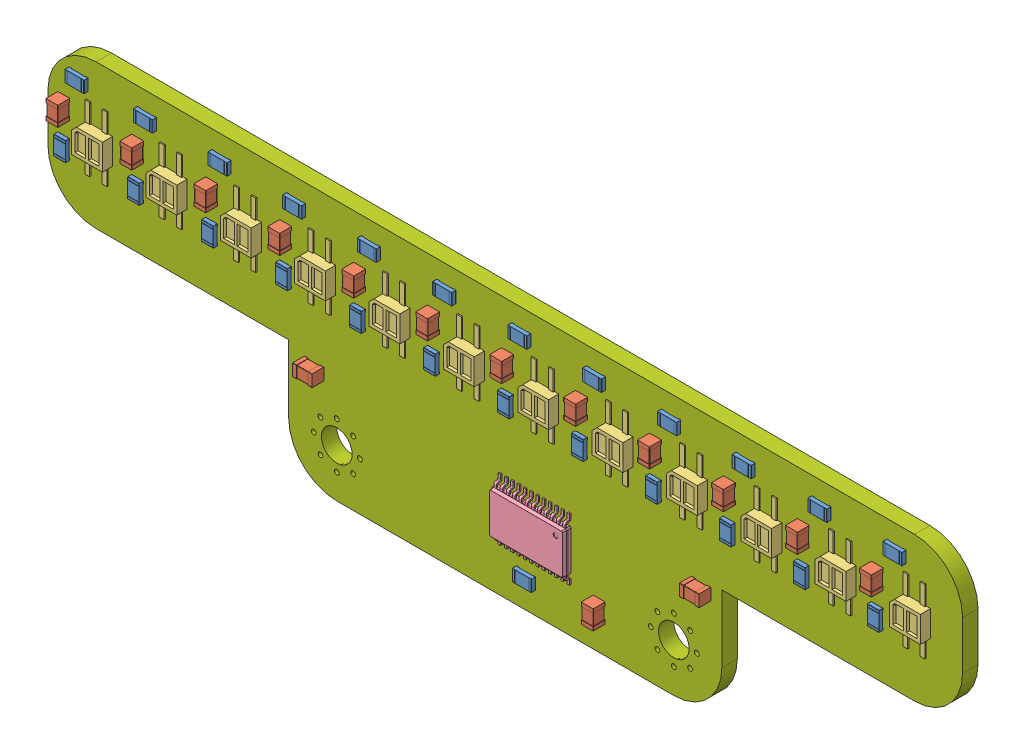
SolidWorks assembly line_sensor, configuration Valor predeterminado. Lengths in mm.
Overall size (95 27 9.2).
118 component instances, 7 part files, 0 mates.
Components (placement in the parent):
- line_sensor.step-1: line_sensor.step [Valor predeterminado] at origin size (95 27 9.2)
  - R_0805_2012Metric.step-1: R_0805_2012Metric.step [Valor predeterminado] at (154.5 -117.25 1.65) size (2 1.2 0.45)
    - R_0805_2012Metric-0.step-1: R_0805_2012Metric-0.step [Valor predeterminado] at origin size (2 1.2 0.45)
  - R_0805_2012Metric.step-2: R_0805_2012Metric.step [Valor predeterminado] at (160.2727 -102.401 1.65) x (0 -1 0) z (0 0 1) size (2 1.2 0.45)
    - R_0805_2012Metric-0.step-1: R_0805_2012Metric-0.step [Valor predeterminado] at origin size (2 1.2 0.45)
  - R_0805_2012Metric.step-3: R_0805_2012Metric.step [Valor predeterminado] at (146.237 -95.601 1.65) size (2 1.2 0.45)
    - R_0805_2012Metric-0.step-1: R_0805_2012Metric-0.step [Valor predeterminado] at origin size (2 1.2 0.45)
  - C_0805_2012Metric.step-1: C_0805_2012Metric.step [Valor predeterminado] at (129.5455 -98.8 1.65) x (0 -1 0) z (0 0 1) size (2 1.25 1.25)
    - C_0805_2012Metric-1.step-1: C_0805_2012Metric-1.step [Valor predeterminado] at origin size (2 1.25 1.25)
  - R_0805_2012Metric.step-4: R_0805_2012Metric.step [Valor predeterminado] at (122.9 -95.601 1.65) size (2 1.2 0.45)
    - R_0805_2012Metric-0.step-1: R_0805_2012Metric-0.step [Valor predeterminado] at origin size (2 1.2 0.45)
  - R_0805_2012Metric.step-5: R_0805_2012Metric.step [Valor predeterminado] at (185.2 -95.6 1.65) size (2 1.2 0.45)
    - R_0805_2012Metric-0.step-1: R_0805_2012Metric-0.step [Valor predeterminado] at origin size (2 1.2 0.45)
  - R_0805_2012Metric.step-6: R_0805_2012Metric.step [Valor predeterminado] at (115.15 -95.601 1.65) size (2 1.2 0.45)
    - R_0805_2012Metric-0.step-1: R_0805_2012Metric-0.step [Valor predeterminado] at origin size (2 1.2 0.45)
  - C_0805_2012Metric.step-2: C_0805_2012Metric.step [Valor predeterminado] at (160.2727 -98.801 1.65) x (0 -1 0) z (0 0 1) size (2 1.25 1.25)
    - C_0805_2012Metric-1.step-1: C_0805_2012Metric-1.step [Valor predeterminado] at origin size (2 1.25 1.25)
  - C_0805_2012Metric.step-3: C_0805_2012Metric.step [Valor predeterminado] at (172.7 -109.1 1.65) size (2 1.25 1.25)
    - C_0805_2012Metric-1.step-1: C_0805_2012Metric-1.step [Valor predeterminado] at origin size (2 1.25 1.25)
  - C_0805_2012Metric.step-4: C_0805_2012Metric.step [Valor predeterminado] at (152.5909 -98.801 1.65) x (0 -1 0) z (0 0 1) size (2 1.25 1.25)
    - C_0805_2012Metric-1.step-1: C_0805_2012Metric-1.step [Valor predeterminado] at origin size (2 1.25 1.25)
  - R_0805_2012Metric.step-7: R_0805_2012Metric.step [Valor predeterminado] at (183.3182 -102.401 1.65) x (0 -1 0) z (0 0 1) size (2 1.2 0.45)
    - R_0805_2012Metric-0.step-1: R_0805_2012Metric-0.step [Valor predeterminado] at origin size (2 1.2 0.45)
  - R_0805_2012Metric.step-8: R_0805_2012Metric.step [Valor predeterminado] at (191 -102.401 1.65) x (0 -1 0) z (0 0 1) size (2 1.2 0.45)
    - R_0805_2012Metric-0.step-1: R_0805_2012Metric-0.step [Valor predeterminado] at origin size (2 1.2 0.45)
  - R_0805_2012Metric.step-9: R_0805_2012Metric.step [Valor predeterminado] at (154.037 -95.601 1.65) size (2 1.2 0.45)
    - R_0805_2012Metric-0.step-1: R_0805_2012Metric-0.step [Valor predeterminado] at origin size (2 1.2 0.45)
  - Everlight_ITR8307.step-1: Everlight_ITR8307.step [Valor predeterminado] at (194.863 -100.4 1.65) size (3.2 6.7 1.4)
    - Everlight_ITR8307-2.step-1: Everlight_ITR8307-2.step [Valor predeterminado] at origin size (3.2 6.7 1.4)
  - R_0805_2012Metric.step-10: R_0805_2012Metric.step [Valor predeterminado] at (161.8 -95.601 1.65) size (2 1.2 0.45)
    - R_0805_2012Metric-0.step-1: R_0805_2012Metric-0.step [Valor predeterminado] at origin size (2 1.2 0.45)
  - Everlight_ITR8307.step-2: Everlight_ITR8307.step [Valor predeterminado] at (140.8039 -100.4 1.65) size (3.2 6.7 1.4)
    - Everlight_ITR8307-2.step-1: Everlight_ITR8307-2.step [Valor predeterminado] at origin size (3.2 6.7 1.4)
  - R_0805_2012Metric.step-11: R_0805_2012Metric.step [Valor predeterminado] at (138.4 -95.601 1.65) size (2 1.2 0.45)
    - R_0805_2012Metric-0.step-1: R_0805_2012Metric-0.step [Valor predeterminado] at origin size (2 1.2 0.45)
  - C_0805_2012Metric.step-5: C_0805_2012Metric.step [Valor predeterminado] at (167.9545 -98.801 1.65) x (0 -1 0) z (0 0 1) size (2 1.25 1.25)
    - C_0805_2012Metric-1.step-1: C_0805_2012Metric-1.step [Valor predeterminado] at origin size (2 1.25 1.25)
  - R_0805_2012Metric.step-12: R_0805_2012Metric.step [Valor predeterminado] at (137.2273 -102.401 1.65) x (0 -1 0) z (0 0 1) size (2 1.2 0.45)
    - R_0805_2012Metric-0.step-1: R_0805_2012Metric-0.step [Valor predeterminado] at origin size (2 1.2 0.45)
  - R_0805_2012Metric.step-13: R_0805_2012Metric.step [Valor predeterminado] at (121.8636 -102.401 1.65) x (0 -1 0) z (0 0 1) size (2 1.2 0.45)
    - R_0805_2012Metric-0.step-1: R_0805_2012Metric-0.step [Valor predeterminado] at origin size (2 1.2 0.45)
  - Everlight_ITR8307.step-3: Everlight_ITR8307.step [Valor predeterminado] at (117.6357 -100.4 1.65) size (3.2 6.7 1.4)
    - Everlight_ITR8307-2.step-1: Everlight_ITR8307-2.step [Valor predeterminado] at origin size (3.2 6.7 1.4)
  - R_0805_2012Metric.step-14: R_0805_2012Metric.step [Valor predeterminado] at (169.6 -95.601 1.65) size (2 1.2 0.45)
    - R_0805_2012Metric-0.step-1: R_0805_2012Metric-0.step [Valor predeterminado] at origin size (2 1.2 0.45)
  - R_0805_2012Metric.step-15: R_0805_2012Metric.step [Valor predeterminado] at (108.05 -95.601 1.65) size (2 1.2 0.45)
    - R_0805_2012Metric-0.step-1: R_0805_2012Metric-0.step [Valor predeterminado] at origin size (2 1.2 0.45)
  - Everlight_ITR8307.step-4: Everlight_ITR8307.step [Valor predeterminado] at (148.5266 -100.4 1.65) size (3.2 6.7 1.4)
    - Everlight_ITR8307-2.step-1: Everlight_ITR8307-2.step [Valor predeterminado] at origin size (3.2 6.7 1.4)
  - R_0805_2012Metric.step-16: R_0805_2012Metric.step [Valor predeterminado] at (152.5909 -102.401 1.65) x (0 -1 0) z (0 0 1) size (2 1.2 0.45)
    - R_0805_2012Metric-0.step-1: R_0805_2012Metric-0.step [Valor predeterminado] at origin size (2 1.2 0.45)
  - C_0805_2012Metric.step-6: C_0805_2012Metric.step [Valor predeterminado] at (137.2273 -98.801 1.65) x (0 -1 0) z (0 0 1) size (2 1.25 1.25)
    - C_0805_2012Metric-1.step-1: C_0805_2012Metric-1.step [Valor predeterminado] at origin size (2 1.25 1.25)
  - C_0805_2012Metric.step-7: C_0805_2012Metric.step [Valor predeterminado] at (144.9091 -98.801 1.65) x (0 -1 0) z (0 0 1) size (2 1.25 1.25)
    - C_0805_2012Metric-1.step-1: C_0805_2012Metric-1.step [Valor predeterminado] at origin size (2 1.25 1.25)
  - TSSOP-24_4.4x7.8mm_P0.65mm.step-1: TSSOP-24_4.4x7.8mm_P0.65mm.step [Valor predeterminado] at (155.473 -112.304 1.65) x (0 -1 0) z (0 0 1) size (6.4 7.8 0.97)
    - TSSOP_24_44x78mm_P065mm.step-1: TSSOP_24_44x78mm_P065mm.step [Valor predeterminado] at origin size (6.4 7.8 0.97)
  - Everlight_ITR8307.step-5: Everlight_ITR8307.step [Valor predeterminado] at (156.2494 -100.4 1.65) size (3.2 6.7 1.4)
    - Everlight_ITR8307-2.step-1: Everlight_ITR8307-2.step [Valor predeterminado] at origin size (3.2 6.7 1.4)
  - C_0805_2012Metric.step-8: C_0805_2012Metric.step [Valor predeterminado] at (106.5 -98.801 1.65) x (0 -1 0) z (0 0 1) size (2 1.25 1.25)
    - C_0805_2012Metric-1.step-1: C_0805_2012Metric-1.step [Valor predeterminado] at origin size (2 1.25 1.25)
  - R_0805_2012Metric.step-17: R_0805_2012Metric.step [Valor predeterminado] at (177.337 -95.601 1.65) size (2 1.2 0.45)
    - R_0805_2012Metric-0.step-1: R_0805_2012Metric-0.step [Valor predeterminado] at origin size (2 1.2 0.45)
  - Everlight_ITR8307.step-6: Everlight_ITR8307.step [Valor predeterminado] at (171.6948 -100.4 1.65) size (3.2 6.7 1.4)
    - Everlight_ITR8307-2.step-1: Everlight_ITR8307-2.step [Valor predeterminado] at origin size (3.2 6.7 1.4)
  - R_0805_2012Metric.step-18: R_0805_2012Metric.step [Valor predeterminado] at (175.6364 -102.401 1.65) x (0 -1 0) z (0 0 1) size (2 1.2 0.45)
    - R_0805_2012Metric-0.step-1: R_0805_2012Metric-0.step [Valor predeterminado] at origin size (2 1.2 0.45)
  - R_0805_2012Metric.step-19: R_0805_2012Metric.step [Valor predeterminado] at (130.65 -95.6 1.65) size (2 1.2 0.45)
    - R_0805_2012Metric-0.step-1: R_0805_2012Metric-0.step [Valor predeterminado] at origin size (2 1.2 0.45)
  - C_0805_2012Metric.step-9: C_0805_2012Metric.step [Valor predeterminado] at (114.1818 -98.801 1.65) x (0 -1 0) z (0 0 1) size (2 1.25 1.25)
    - C_0805_2012Metric-1.step-1: C_0805_2012Metric-1.step [Valor predeterminado] at origin size (2 1.25 1.25)
  - Everlight_ITR8307.step-7: Everlight_ITR8307.step [Valor predeterminado] at (133.0812 -100.399 1.65) size (3.2 6.7 1.4)
    - Everlight_ITR8307-2.step-1: Everlight_ITR8307-2.step [Valor predeterminado] at origin size (3.2 6.7 1.4)
  - Everlight_ITR8307.step-8: Everlight_ITR8307.step [Valor predeterminado] at (109.913 -100.4 1.65) size (3.2 6.7 1.4)
    - Everlight_ITR8307-2.step-1: Everlight_ITR8307-2.step [Valor predeterminado] at origin size (3.2 6.7 1.4)
  - Everlight_ITR8307.step-9: Everlight_ITR8307.step [Valor predeterminado] at (163.9721 -100.4 1.65) size (3.2 6.7 1.4)
    - Everlight_ITR8307-2.step-1: Everlight_ITR8307-2.step [Valor predeterminado] at origin size (3.2 6.7 1.4)
  - Everlight_ITR8307.step-10: Everlight_ITR8307.step [Valor predeterminado] at (179.4175 -100.4 1.65) size (3.2 6.7 1.4)
    - Everlight_ITR8307-2.step-1: Everlight_ITR8307-2.step [Valor predeterminado] at origin size (3.2 6.7 1.4)
  - C_0805_2012Metric.step-10: C_0805_2012Metric.step [Valor predeterminado] at (175.6364 -98.801 1.65) x (0 -1 0) z (0 0 1) size (2 1.25 1.25)
    - C_0805_2012Metric-1.step-1: C_0805_2012Metric-1.step [Valor predeterminado] at origin size (2 1.25 1.25)
  - R_0805_2012Metric.step-20: R_0805_2012Metric.step [Valor predeterminado] at (114.1818 -102.401 1.65) x (0 -1 0) z (0 0 1) size (2 1.2 0.45)
    - R_0805_2012Metric-0.step-1: R_0805_2012Metric-0.step [Valor predeterminado] at origin size (2 1.2 0.45)
  - C_0805_2012Metric.step-11: C_0805_2012Metric.step [Valor predeterminado] at (121.8636 -98.801 1.65) x (0 -1 0) z (0 0 1) size (2 1.25 1.25)
    - C_0805_2012Metric-1.step-1: C_0805_2012Metric-1.step [Valor predeterminado] at origin size (2 1.25 1.25)
  - Everlight_ITR8307.step-11: Everlight_ITR8307.step [Valor predeterminado] at (125.3585 -100.4 1.65) size (3.2 6.7 1.4)
    - Everlight_ITR8307-2.step-1: Everlight_ITR8307-2.step [Valor predeterminado] at origin size (3.2 6.7 1.4)
  - R_0805_2012Metric.step-21: R_0805_2012Metric.step [Valor predeterminado] at (167.9545 -102.401 1.65) x (0 -1 0) z (0 0 1) size (2 1.2 0.45)
    - R_0805_2012Metric-0.step-1: R_0805_2012Metric-0.step [Valor predeterminado] at origin size (2 1.2 0.45)
  - C_0805_2012Metric.step-12: C_0805_2012Metric.step [Valor predeterminado] at (132.5125 -109.4 1.65) x (-1 0 0) z (0 0 1) size (2 1.25 1.25)
    - C_0805_2012Metric-1.step-1: C_0805_2012Metric-1.step [Valor predeterminado] at origin size (2 1.25 1.25)
  - Everlight_ITR8307.step-12: Everlight_ITR8307.step [Valor predeterminado] at (187.1403 -100.4 1.65) size (3.2 6.7 1.4)
    - Everlight_ITR8307-2.step-1: Everlight_ITR8307-2.step [Valor predeterminado] at origin size (3.2 6.7 1.4)
  - R_0805_2012Metric.step-22: R_0805_2012Metric.step [Valor predeterminado] at (193 -95.601 1.65) size (2 1.2 0.45)
    - R_0805_2012Metric-0.step-1: R_0805_2012Metric-0.step [Valor predeterminado] at origin size (2 1.2 0.45)
  - C_0805_2012Metric.step-13: C_0805_2012Metric.step [Valor predeterminado] at (162.1 -116.3 1.65) x (0 -1 0) z (0 0 1) size (2 1.25 1.25)
    - C_0805_2012Metric-1.step-1: C_0805_2012Metric-1.step [Valor predeterminado] at origin size (2 1.25 1.25)
  - C_0805_2012Metric.step-14: C_0805_2012Metric.step [Valor predeterminado] at (191 -98.801 1.65) x (0 -1 0) z (0 0 1) size (2 1.25 1.25)
    - C_0805_2012Metric-1.step-1: C_0805_2012Metric-1.step [Valor predeterminado] at origin size (2 1.25 1.25)
  - R_0805_2012Metric.step-23: R_0805_2012Metric.step [Valor predeterminado] at (144.9091 -102.401 1.65) x (0 -1 0) z (0 0 1) size (2 1.2 0.45)
    - R_0805_2012Metric-0.step-1: R_0805_2012Metric-0.step [Valor predeterminado] at origin size (2 1.2 0.45)
  - C_0805_2012Metric.step-15: C_0805_2012Metric.step [Valor predeterminado] at (183.3182 -98.801 1.65) x (0 -1 0) z (0 0 1) size (2 1.25 1.25)
    - C_0805_2012Metric-1.step-1: C_0805_2012Metric-1.step [Valor predeterminado] at origin size (2 1.25 1.25)
  - R_0805_2012Metric.step-24: R_0805_2012Metric.step [Valor predeterminado] at (129.5455 -102.4 1.65) x (0 -1 0) z (0 0 1) size (2 1.2 0.45)
    - R_0805_2012Metric-0.step-1: R_0805_2012Metric-0.step [Valor predeterminado] at origin size (2 1.2 0.45)
  - R_0805_2012Metric.step-25: R_0805_2012Metric.step [Valor predeterminado] at (106.5 -102.401 1.65) x (0 -1 0) z (0 0 1) size (2 1.2 0.45)
    - R_0805_2012Metric-0.step-1: R_0805_2012Metric-0.step [Valor predeterminado] at origin size (2 1.2 0.45)
  - LED_0805_2012Metric.step-1: LED_0805_2012Metric.step [Valor predeterminado] at (152.2515 -99.7082 -0.05) x (0 1 0) z (0 0 -1) size (2 1.25 1.1)
    - LED_0805_2012Metric-3.step-1: LED_0805_2012Metric-3.step [Valor predeterminado] at origin size (2 1.25 1.1)
  - R_0805_2012Metric.step-26: R_0805_2012Metric.step [Valor predeterminado] at (154.395 -99.7482 -0.05) x (0 1 0) z (0 0 -1) size (2 1.2 0.45)
    - R_0805_2012Metric-0.step-1: R_0805_2012Metric-0.step [Valor predeterminado] at origin size (2 1.2 0.45)
  - C_0805_2012Metric.step-16: C_0805_2012Metric.step [Valor predeterminado] at (153.3945 -102.4183 -0.05) x (-1 0 0) z (0 0 -1) size (2 1.25 1.25)
    - C_0805_2012Metric-1.step-1: C_0805_2012Metric-1.step [Valor predeterminado] at origin size (2 1.25 1.25)
  - JST_PH_S8B-PH-K_1x08_P2.00mm_Horizontal.step-1: JST_PH_S8B-PH-K_1x08_P2.00mm_Horizontal.step [Valor predeterminado] at (145.3 -109.991 -0.05) x (1 0 0) z (0 -1 0) size (17.9 7.6 8.25)
    - JST_S8B_PH_K.step-1: JST_S8B_PH_K.step [Valor predeterminado] at origin size (17.9 7.6 8.25)
  - R_0805_2012Metric.step-27: R_0805_2012Metric.step [Valor predeterminado] at (164.53 -107.92 -0.05) x (0 1 0) z (0 0 -1) size (2 1.2 0.45)
    - R_0805_2012Metric-0.step-1: R_0805_2012Metric-0.step [Valor predeterminado] at origin size (2 1.2 0.45)
  - line_sensor_PCB.step-1: line_sensor_PCB.step [Valor predeterminado] at origin size (95 27 1.6)
